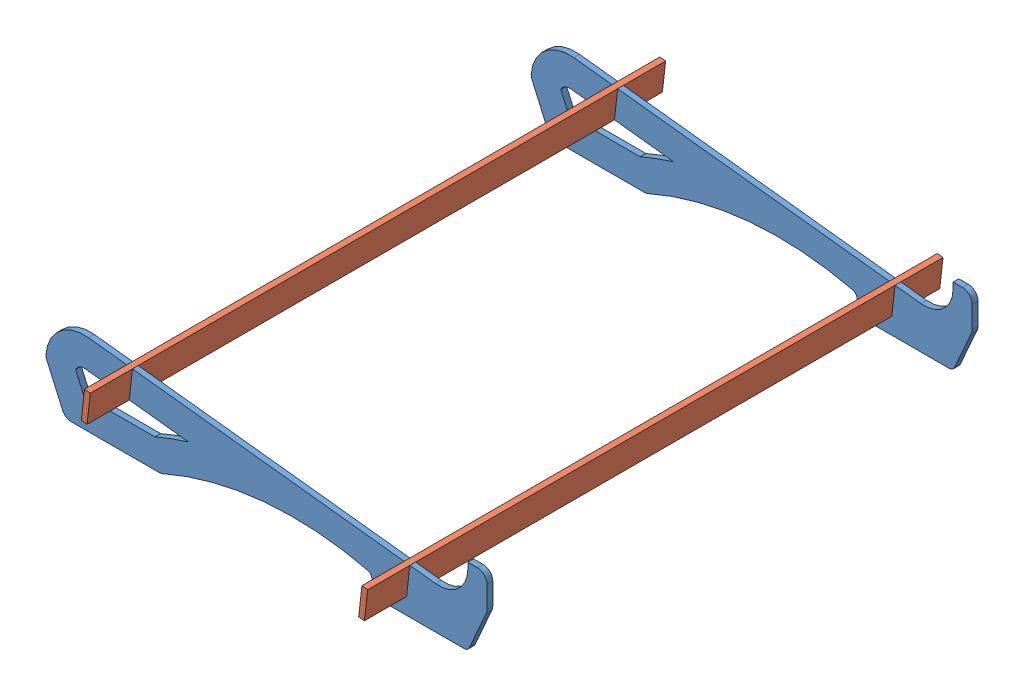
SolidWorks assembly laptopstand, configuration Default. Lengths in mm.
Overall size (229.97 42.6 300).
4 component instances, 2 part files, 9 mates.
Components (placement in the parent):
- laptopstand1-1: laptopstand1 [Default] at (-164.3325 153.2842 285.9268) size (229.97 42.6 3)
- laptopstand1-2: laptopstand1 [Default] at (-164.3325 153.2842 32.9268) size (229.97 42.6 3)
- cross-1: cross [Default] at (41.671 224.7142 284.1565) x (0.993605 -0.11291 0) z (0 0 1) size (3 15 300)
- cross-2: cross [Default] at (186.293 208.2799 284.1565) x (0.993605 -0.11291 0) z (0 0 1) size (3 15 300)
Mates (geometry in assembly coordinates):
- Distance1: distance = 250 mm anti-aligned: plane of laptopstand1-1 through (17.4202 188.59 285.9268) normal (0 0 -1); plane of laptopstand1-2 through (17.4202 188.59 35.9268) normal (0 0 1)
- Coincident2: coincident aligned: plane of laptopstand1-1 through (226.9925 187.6235 288.9268) normal (0.914468 -0.404658 0); plane of laptopstand1-2 through (226.9925 187.6235 35.9268) normal (0.914468 -0.404658 0)
- Coincident3: coincident aligned: plane of laptopstand1-1 through (19.6784 208.4621 288.9268) normal (0.11291 0.993605 0); plane of laptopstand1-2 through (19.6784 208.4621 35.9268) normal (0.11291 0.993605 0)
- Coincident4: coincident aligned: plane of laptopstand1-1 through (19.6784 208.4621 288.9268) normal (0.11291 0.993605 0); plane of cross-1 through (42.5481 205.8632 310.9268) normal (0.11291 0.993605 0)
- Width1: width anti-aligned: plane of cross-1 through (42.5481 205.8632 310.9268) normal (0 0 1); plane of cross-1 through (42.5481 205.8632 10.9268) normal (0 0 -1); plane of laptopstand1-2 through (17.4202 188.59 32.9268) normal (0 0 -1); plane of laptopstand1-1 through (17.4202 188.59 288.9268) normal (0 0 1)
- Distance2: distance = 30 mm anti-aligned: plane of cross-1 through (41.671 224.7142 284.1565) normal (-0.993605 0.11291 0); cylinder of laptopstand1-1 through (2.4525 189.5738 288.9268) axis (0 0 -1) radius 5
- Width2: width aligned: plane of cross-2 through (187.1702 189.4289 310.9268) normal (0 0 1); plane of cross-2 through (187.1702 189.4289 10.9268) normal (0 0 -1); plane of laptopstand1-2 through (17.4202 188.59 32.9268) normal (0 0 -1); plane of laptopstand1-1 through (17.4202 188.59 288.9268) normal (0 0 1)
- Coincident5: coincident aligned: plane of laptopstand1-1 through (19.6784 208.4621 288.9268) normal (0.11291 0.993605 0); plane of cross-2 through (187.1702 189.4289 310.9268) normal (0.11291 0.993605 0)
- Distance3: distance = 30 mm anti-aligned: plane of cross-2 through (189.2738 207.9411 284.1565) normal (0.993605 -0.11291 0); cylinder of laptopstand1-1 through (222.4202 189.6468 288.9268) axis (0 0 -1) radius 5
